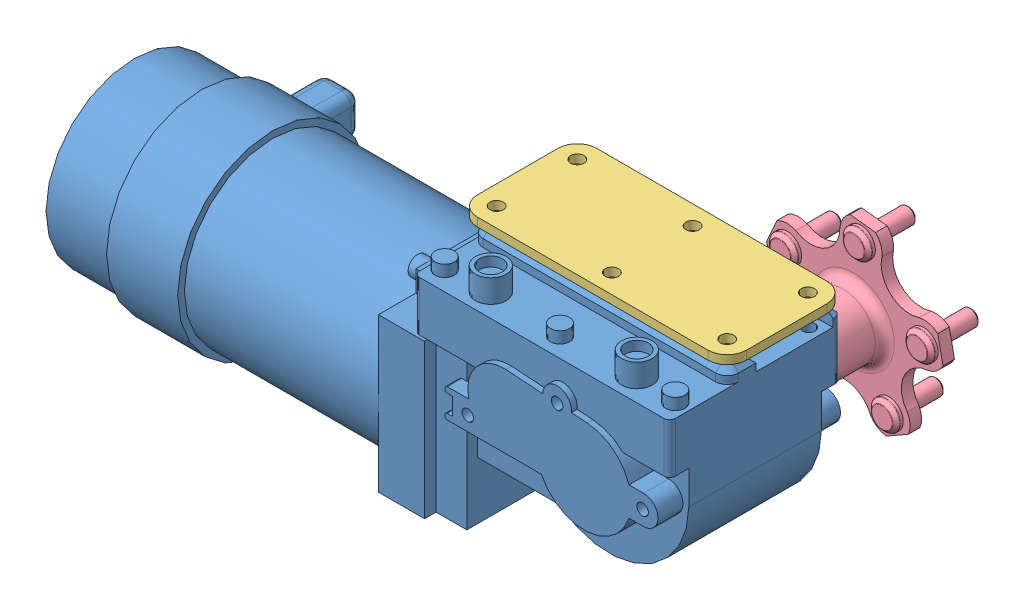
SolidWorks assembly motor assem, configuration Default. Lengths in mm.
Overall size (338.32 133.71 167).
4 component instances, 4 part files, 9 mates.
Components (placement in the parent):
- motor body-1: motor body [Default] at origin size (323 128 159)
- pin-1: pin [Default] at (0 -23.547 -79.7998) x (1 0 0) z (0 -1 0) size (6 40 6)
- connection plate-1: connection plate [Default] at (15.9331 20.25 -552.5501) size (140 4.5 62)
- Motor Coupler-1: Motor Coupler [Default] at (77.2002 -34.5 -63.8999) x (0.410997 0.911637 0) z (0 0 1) size (92.43 87.91 67)
Mates (geometry in assembly coordinates):
- Coincident1: coincident anti-aligned: plane of motor body-1 through (80.2002 -25.547 -19.8999) normal (-1 0 0); plane of pin-1 through (80.2002 -29.547 -22.8999) normal (1 0 0)
- Coincident2: coincident anti-aligned: plane of motor body-1 through (80.2002 -29.547 -19.8999) normal (0 1 0); plane of pin-1 through (77.2002 -29.547 -56.8999) normal (0 -1 0)
- Tangent1: tangent anti-aligned: plane of motor body-1 through (0 0 -19.8999) normal (0 0 -1); cylinder of pin-1 through (77.2002 -29.547 -22.8999) axis (0 1 0) radius 3
- Concentric1: concentric aligned: circle of motor body-1; circle of connection plate-1
- Coincident3: coordinate: point of motor body-1; point of assembly
- Concentric2: concentric anti-aligned: cylinder of motor body-1 through (-7.7998 3 42.6001) axis (0 1 0) radius 2.5; cylinder of connection plate-1 through (-7.7998 24.75 42.6001) axis (0 -1 0) radius 3.5
- Concentric30: concentric anti-aligned: cylinder of Motor Coupler-1 through (77.2002 -34.5 -20.9899) axis (0 0 -1) radius 8.5; cylinder of motor body-1 through (77.2002 -34.5 -61.8999) axis (0 0 1) radius 8.5
- Coincident58: coincident anti-aligned: plane of Motor Coupler-1 through (77.2002 -34.5 -15.8999) normal (0 0 1); plane of motor body-1 through (77.2002 -34.5 -15.8999) normal (0 0 -1)
- Coincident59: coincident anti-aligned: plane of motor body-1 through (-8.2998 17 43.1001) normal (0 1 0); plane of connection plate-1 through (-7.7998 17 42.6001) normal (0 -1 0)
